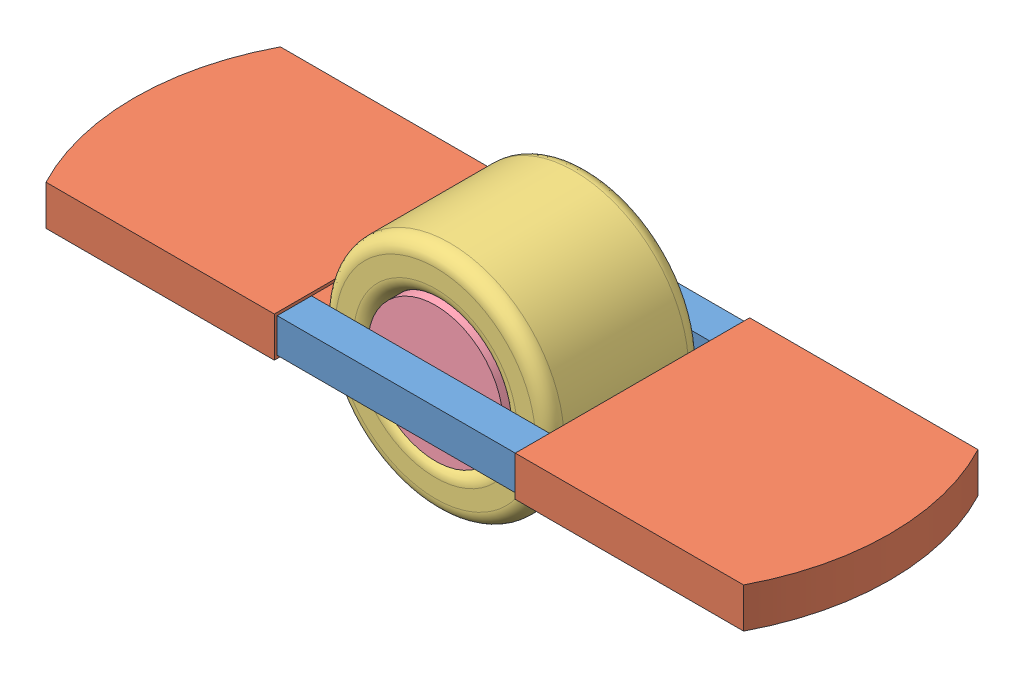
SolidWorks assembly Onewheel, configuration Default. Lengths in mm.
Overall size (839.06 254 260.35).
6 component instances, 4 part files, 16 mates.
Components (placement in the parent):
- Frame Sides-1: Frame Sides [Default] at (-363.1112 -24.2349 30.0029) size (762 38.1 38.1)
- Enclosure-1: Enclosure [Default] at (-147.8586 -27.4099 33.1779) size (285.75 44.45 260.35)
- Frame Sides-2: Frame Sides [Default] at (-363.1112 -24.2349 -185.8971) size (762 38.1 38.1)
- Enclosure-2: Enclosure [Default] at (119.6969 -27.4099 -227.1721) x (-1 0 0) z (0 0 -1) size (285.75 44.45 260.35)
- Wheel-1: Wheel [Default] at (-14.0809 -5.1849 -181.9971) x (-1 0 0) z (0 0 1) size (254 254 170)
- Hub motor-1: Hub motor [Default] at (-14.0809 -5.1849 -181.9971) size (150 150 170)
Mates (geometry in assembly coordinates):
- Coincident1: coincident anti-aligned: plane of Frame Sides-1 through (-363.1112 -24.2349 30.0029) normal (0 0 1); plane of Enclosure-1 through (-147.8586 -27.4099 30.0029) normal (0 0 -1)
- Coincident3: coincident anti-aligned: plane of Frame Sides-1 through (-363.1112 -24.2349 -8.0971) normal (0 -1 0); plane of Enclosure-1 through (-363.1112 -24.2349 -223.9971) normal (0 1 0)
- Coincident4: coincident anti-aligned: plane of Frame Sides-1 through (-395.0809 13.8651 -8.0971) normal (-0.766044 -0.642788 0); plane of Enclosure-1 through (-395.0809 13.8651 -223.9971) normal (0.766044 0.642788 0)
- Coincident5: coincident anti-aligned: plane of Enclosure-1 through (-147.8586 -27.4099 -223.9971) normal (0 0 1); plane of Frame Sides-2 through (-363.1112 -24.2349 -223.9971) normal (0 0 -1)
- Coincident6: coincident anti-aligned: plane of Enclosure-1 through (-363.1112 -24.2349 -223.9971) normal (0 1 0); plane of Frame Sides-2 through (-363.1112 -24.2349 -223.9971) normal (0 -1 0)
- Coincident7: coincident anti-aligned: plane of Enclosure-1 through (-395.0809 13.8651 -223.9971) normal (0.766044 0.642788 0); plane of Frame Sides-2 through (-395.0809 13.8651 -223.9971) normal (-0.766044 -0.642788 0)
- Coincident8: coincident anti-aligned: plane of Frame Sides-2 through (-363.1112 -24.2349 -223.9971) normal (0 0 -1); plane of Enclosure-2 through (119.6969 -27.4099 -223.9971) normal (0 0 1)
- Coincident9: coincident anti-aligned: plane of Frame Sides-2 through (-395.0809 13.8651 -223.9971) normal (0 1 0); plane of Enclosure-2 through (366.9191 13.8651 30.0029) normal (0 -1 0)
- Coincident10: coincident anti-aligned: plane of Frame Sides-2 through (366.9191 13.8651 -223.9971) normal (0.766044 -0.642788 0); plane of Enclosure-2 through (366.9191 13.8651 30.0029) normal (-0.766044 0.642788 0)
- Concentric1: concentric: cylinder of Wheel-1 through (-14.0809 -5.1849 -181.9971) axis (0 0 1) radius 75; cylinder of Hub motor-1 through (-14.0809 -5.1849 -11.9971) axis (0 0 -1) radius 75
- Width1: width: plane of Hub motor-1 through (-14.0809 -5.1849 -11.9971) normal (0 0 1); plane of Wheel-1 through (-14.0809 -5.1849 -181.9971) normal (0 0 -1); plane of Hub motor-1 through (-14.0809 -5.1849 -181.9971) normal (0 0 -1); plane of Wheel-1 through (-14.0809 -5.1849 -11.9971) normal (0 0 1)
- Width2: width: plane of Frame Sides-1 through (-363.1112 -24.2349 30.0029) normal (0 0 1); plane of Hub motor-1 through (-363.1112 -24.2349 -223.9971) normal (0 0 -1); plane of Frame Sides-2 through (-14.0809 -5.1849 -181.9971) normal (0 0 -1); plane of Hub motor-1 through (-14.0809 -5.1849 -11.9971) normal (0 0 1)
- Width3: width: plane of assembly; cylinder of assembly; plane of assembly; plane of Frame Sides-1 through (-395.0809 13.8651 -8.0971) normal (0 1 0); plane of Frame Sides-1; cylinder of Hub motor-1
- Width4: width: plane of assembly; cylinder of assembly; plane of assembly; plane of Frame Sides-1 through (-395.0809 13.8651 -8.0971) normal (-0.766044 -0.642788 0); plane of Frame Sides-1; cylinder of Hub motor-1
- Parallel1: parallel anti-aligned: plane of Wheel-1 through (-14.0809 -5.1849 -181.9971) normal (0 -1 0)
- Coincident15: coincident anti-aligned: plane of Wheel-1 through (-14.0809 -5.1849 -181.9971) normal (0 -1 0); plane of Hub motor-1 through (-14.0809 -5.1849 -181.9971) normal (0 1 0)
